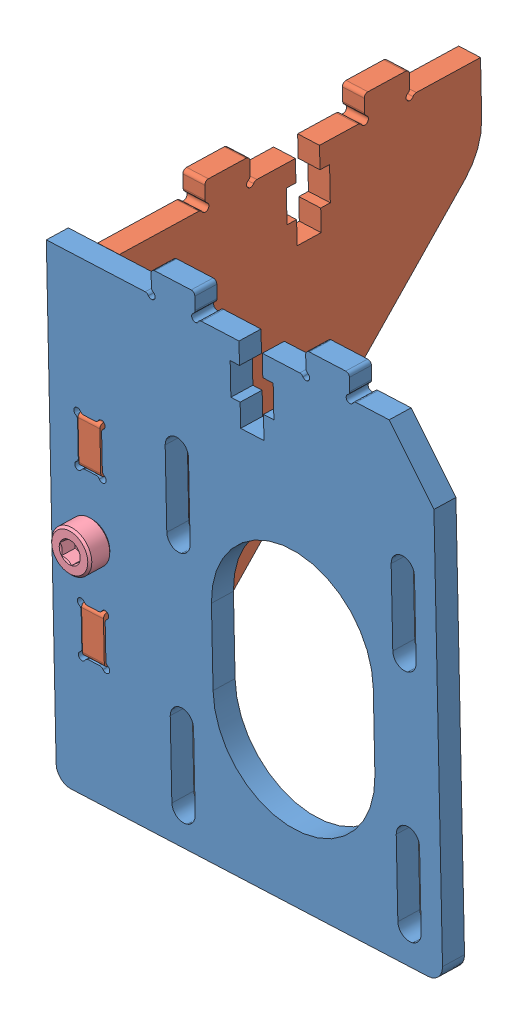
SolidWorks assembly Y-Motor-mount, configuration Default. Lengths in mm.
Overall size (56.01 67.48 56.34).
4 component instances, 4 part files, 8 mates.
Components (placement in the parent):
- Y-Axis-Motor-Mount-front-1: Y-Axis-Motor-Mount-front [Default] at (38.5196 15.1092 70.2367) x (0.998888 0.047105 0.00186) z (-0.00302 0.024568 0.999694) size (53 65 3)
- Y-Axis-Motor-Mount-bottom-1: Y-Axis-Motor-Mount-bottom [Default] at (323.8552 80.0232 292.6918) x (-0.047045 0.998588 -0.024683) z (-0.998888 -0.047105 -0.00186) size (58.68 52.33 3)
- 90576A102_ZINC-PLATED CLASS 8 STL NYLON-INSERT LOCKNUT-1: 90576A102_ZINC-PLATED CLASS 8 STL NYLON-INSERT LOCKNUT [90576A102] at (316.4422 214.4296 63.3769) x (0.84154 0.540088 -0.010731) z (-0.540186 0.84125 -0.022306) size (5.5 4.1 6.35)
- 91292A114_TYPE 18-8 SS SOCKET HEAD CAP SCREW-1: 91292A114_TYPE 18-8 SS SOCKET HEAD CAP SCREW [91292A114] at (316.4609 214.2773 57.1788) x (-0.643982 0.76476 -0.02074) z (0.00302 -0.024568 -0.999694) size (5.5 5.5 15.58)
Mates (geometry in assembly coordinates):
- Coincident2: coincident anti-aligned: plane of Y-Axis-Motor-Mount-front-1 through (323.8384 246.8734 65.4027) normal (0.00302 -0.024568 -0.999694); plane of Y-Axis-Motor-Mount-bottom-1 through (314.2361 229.2719 65.8063) normal (-0.00302 0.024568 0.999694)
- Width2: width anti-aligned: plane of Y-Axis-Motor-Mount-front-1 through (317.6652 223.3019 68.9643) normal (-0.998888 -0.047105 -0.00186); plane of Y-Axis-Motor-Mount-front-1 through (314.1588 227.6081 68.8479) normal (0.998888 0.047105 0.00186); plane of Y-Axis-Motor-Mount-bottom-1 through (317.296 228.0354 66.7348) normal (0.998888 0.047105 0.00186); plane of Y-Axis-Motor-Mount-bottom-1 through (314.2993 227.894 66.7292) normal (-0.998888 -0.047105 -0.00186)
- Width3: width anti-aligned: plane of Y-Axis-Motor-Mount-front-1 through (316.5492 228.5875 68.831) normal (0.047045 -0.998588 0.024683); plane of Y-Axis-Motor-Mount-front-1 through (315.2748 222.3224 68.9811) normal (-0.047045 0.998588 -0.024683); plane of Y-Axis-Motor-Mount-bottom-1 through (314.2701 228.4476 68.3927) normal (-0.047045 0.998588 -0.024683); plane of Y-Axis-Motor-Mount-bottom-1 through (314.5648 222.2585 66.8685) normal (0.047045 -0.998588 0.024683)
- Parallel1: parallel aligned: plane of Y-Axis-Motor-Mount-bottom-1 through (315.0816 211.4348 63.4464) normal (-0.047045 0.998588 -0.024683); plane of 90576A102_ZINC-PLATED CLASS 8 STL NYLON-INSERT LOCKNUT-1 through (314.739 217.0027 59.3073) normal (-0.047045 0.998588 -0.024683)
- Concentric1: concentric anti-aligned: cylinder of Y-Axis-Motor-Mount-front-1 through (316.4247 214.5721 69.1751) axis (0.00302 -0.024568 -0.999694) radius 1.6; circle of 90576A102_ZINC-PLATED CLASS 8 STL NYLON-INSERT LOCKNUT-1
- Coincident3: coincident anti-aligned: plane of Y-Axis-Motor-Mount-bottom-1 through (315.0181 212.7829 63.413) normal (0.00302 -0.024568 -0.999694); plane of 90576A102_ZINC-PLATED CLASS 8 STL NYLON-INSERT LOCKNUT-1 through (319.6141 214.5792 63.3828) normal (-0.00302 0.024568 0.999694)
- Coincident4: coincident: plane of Y-Axis-Motor-Mount-front-1 through (323.8294 246.9471 68.4018) normal (-0.00302 0.024568 0.999694); plane of 91292A114_TYPE 18-8 SS SOCKET HEAD CAP SCREW-1 through (316.4247 214.5721 69.1751) normal (0.00302 -0.024568 -0.999694)
- Concentric2: concentric aligned: cylinder of Y-Axis-Motor-Mount-front-1 through (316.4247 214.5721 69.1751) axis (0.00302 -0.024568 -0.999694) radius 1.6; circle of 91292A114_TYPE 18-8 SS SOCKET HEAD CAP SCREW-1
